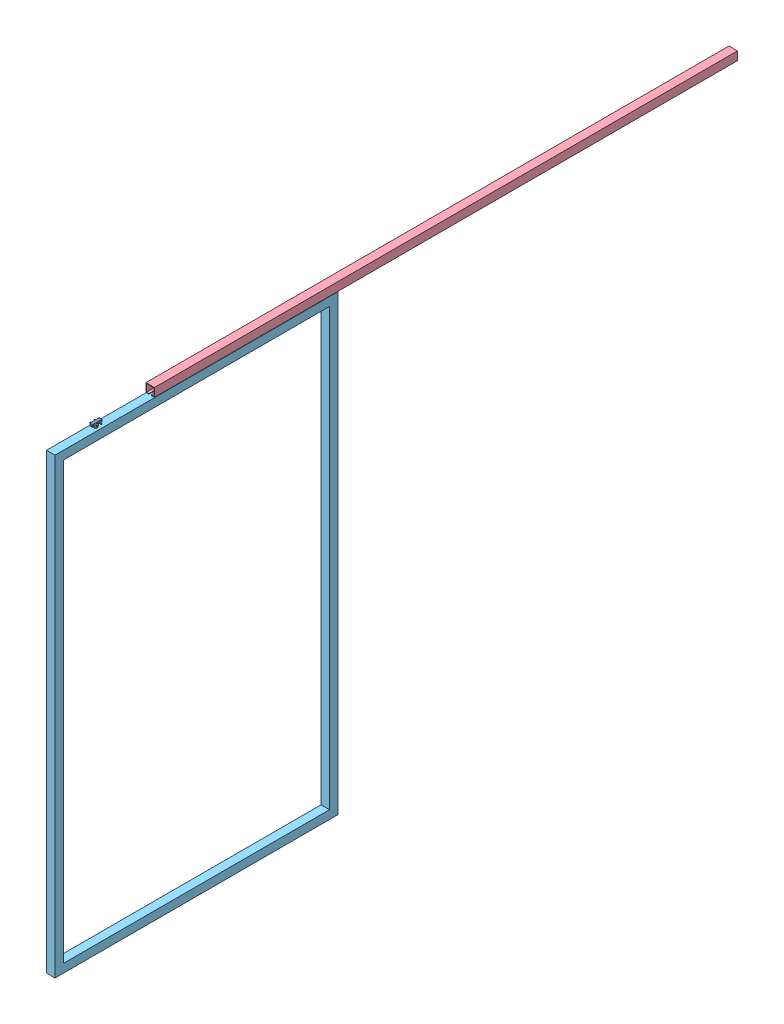
SolidWorks assembly FullDoorWithBar, configuration Default. Lengths in mm.
Overall size (30 1631.25 2411.15).
12 component instances, 5 part files, 13 mates.
Components (placement in the parent):
- FullCar-1: FullCar [Default] at (0 -5.75 1221.8966) size (25 20.7 35.41)
  - Carriage-1: Carriage [Default] at origin size (24.16 15.5 35)
  - LockWheels-1: LockWheels [Default] at (12.5 0 7.5) x (0 0.86398 0.503526) z (0 -0.503526 0.86398) size (3.5 7.63 3.5)
  - LockWheels-2: LockWheels [Default] at (12.5 0 -7.5) x (0 -0.86398 0.503526) z (0 -0.503526 -0.86398) size (3.5 7.63 3.5)
  - LockWheels-3: LockWheels [Default] at (-12.5 0 7.5) x (0 -0.86398 -0.503526) z (0 -0.503526 0.86398) size (3.5 7.63 3.5)
  - LockWheels-4: LockWheels [Default] at (-12.5 0 -7.5) x (0 0.86398 -0.503526) z (0 -0.503526 -0.86398) size (3.5 7.63 3.5)
  - WheelCarriage-1: WheelCarriage [Default] at (8 0 7.5) x (0 -0.634071 0.773275) z (1 0 0) size (14.5 14.5 3.5) (hidden)
  - WheelCarriage-2: WheelCarriage [Default] at (8 0 -7.5) x (0 -0.634071 -0.773275) z (-1 0 0) size (14.5 14.5 3.5) (hidden)
  - WheelCarriage-3: WheelCarriage [Default] at (-8 0 7.5) x (0 -0.634071 0.773275) z (1 0 0) size (14.5 14.5 3.5) (hidden)
  - WheelCarriage-4: WheelCarriage [Default] at (-8 0 -7.5) x (0 -0.634071 -0.773275) z (-1 0 0) size (14.5 14.5 3.5) (hidden)
- FrontHorizontalBar-1: FrontHorizontalBar [Default] at origin size (30 30 2060)
- Door-1: Door [Default] at (0 -816.25 881.1466) x (0 0 1) z (-1 0 0) size (1000 1605 30)
Mates (geometry in assembly coordinates):
- Coincident1: coincident aligned: plane of FrontHorizontalBar-1 through (0 0 0) normal (0 0 1)
- Coincident2: coincident aligned: plane of FrontHorizontalBar-1 through (0 0 0) normal (1 0 0)
- Coincident3: coincident aligned: plane of FrontHorizontalBar-1 through (0 0 0) normal (0 1 0)
- Coincident4: coincident aligned: plane of FullCar-1 through (0 -5.75 1221.8966) normal (1 0 0)
- Tangent1: tangent anti-aligned: cylinder of FullCar-1/WheelCarriage-3 through (-6.25 -5.75 1229.3966) axis (-1 0 0) radius 7.25; plane of FrontHorizontalBar-1 through (-13 -13 1030) normal (0 1 0)
- Tangent2: tangent anti-aligned: cylinder of FullCar-1/WheelCarriage-1 through (9.75 -5.75 1229.3966) axis (-1 0 0) radius 7.25; plane of FrontHorizontalBar-1 through (4 -13 1030) normal (0 1 0)
- Tangent3: tangent anti-aligned: cylinder of FullCar-1/WheelCarriage-4 through (-9.75 -5.75 1214.3966) axis (1 0 0) radius 7.25; plane of FrontHorizontalBar-1 through (-13 -13 1030) normal (0 1 0)
- Tangent4: tangent anti-aligned: cylinder of FullCar-1/WheelCarriage-2 through (6.25 -5.75 1214.3966) axis (1 0 0) radius 7.25; plane of FrontHorizontalBar-1 through (4 -13 1030) normal (0 1 0)
- Coincident5: coincident anti-aligned: plane of Door-1 through (0 -816.25 881.1466) normal (-1 0 0)
- Coincident6: coincident anti-aligned: plane of FullCar-1/Carriage-1 through (0 -11.25 1221.8966) normal (0 -1 0); plane of Door-1 through (0 -11.25 1226.1466) normal (0 1 0)
- Tangent5: tangent: plane of FullCar-1/Carriage-1 through (-3.5 -15 1216.1466) normal (0 0 1); circle of Door-1
- Coincident7: coincident anti-aligned: plane of FullCar-1/Carriage-1 through (0 -11.25 1221.8966) normal (0 -1 0); plane of Door-1 through (0 -11.25 1226.1466) normal (0 1 0)
- Coincident8: coincident: plane of FullCar-1/Carriage-1 through (-3.5 -15 1216.1466) normal (0 0 1); point of Door-1
